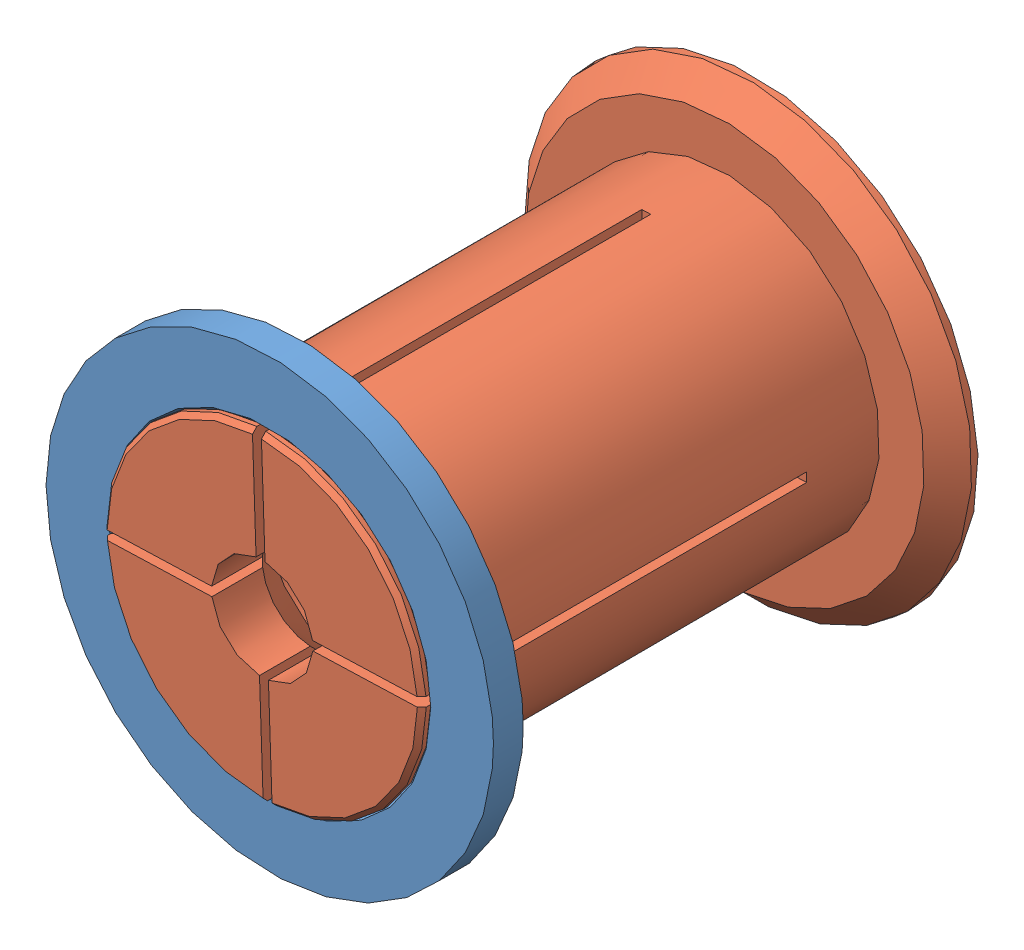
SolidWorks assembly 53-71-17-spool-adapter, configuration Default. Lengths in mm.
Overall size (77.51 77.51 82.5).
2 component instances, 2 part files, 2 mates.
Components (placement in the parent):
- 53-71-17-spool-adapter-female-1: 53-71-17-spool-adapter-female [Default] at (4.7434 31.7057 72.3889) size (75 75 5)
- 53-71-17-spool-adapter-male-1: 53-71-17-spool-adapter-male [Default] at (4.7434 31.7057 1.1389) x (0.999421 0.034015 0) z (0 0 1) size (75 75 82.5)
Mates (geometry in assembly coordinates):
- Concentric1: concentric anti-aligned: cylinder of 53-71-17-spool-adapter-female-1 through (4.7434 31.7057 72.3889) axis (0 0 1) radius 26.25; cylinder of 53-71-17-spool-adapter-male-1 through (4.7434 31.7057 78.6389) axis (0 0 -1) radius 26
- Coincident1: coincident aligned: cone of 53-71-17-spool-adapter-female-1 through (4.7434 31.7057 77.3889) axis (0 0 -1); cone of 53-71-17-spool-adapter-male-1 through (4.7434 31.7057 77.1389) axis (0 0 -1)
